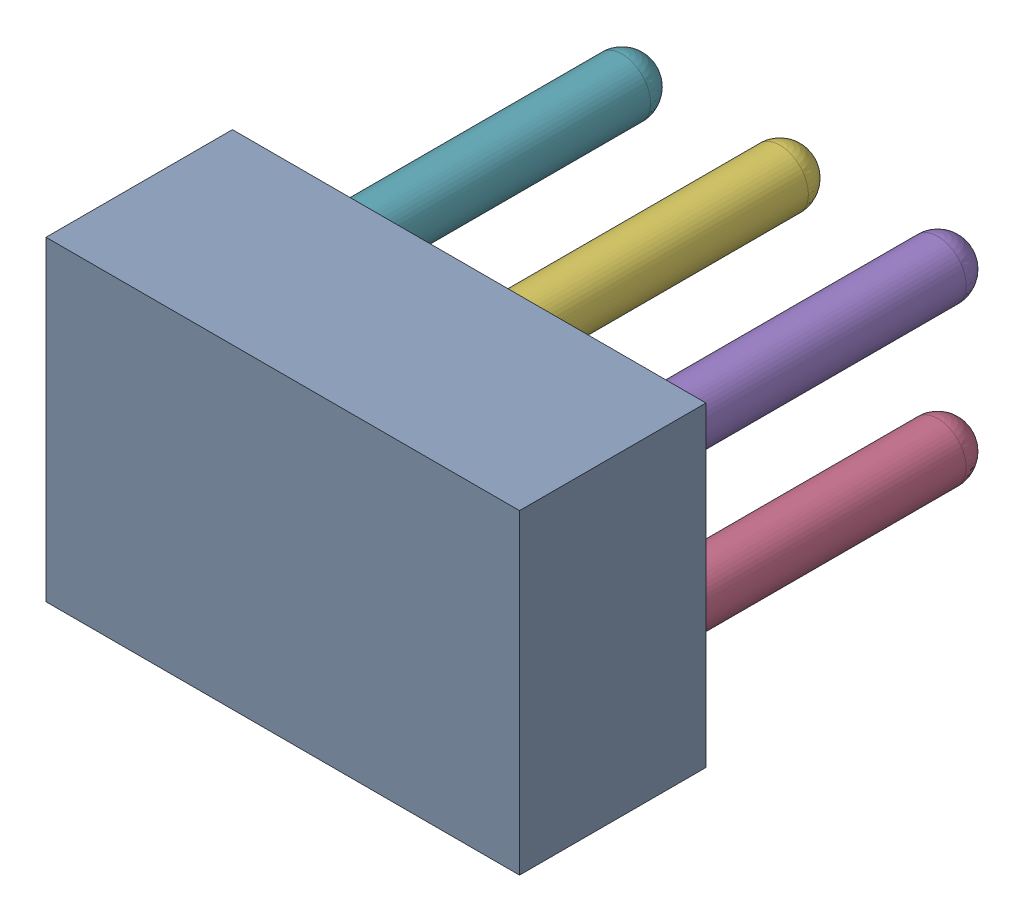
SolidWorks assembly Open CASCADE STEP translator 6.8 1.8.1, configuration Défaut. Lengths in mm.
Overall size (7.62 5.08 8.46).
7 component instances, 7 part files, 0 mates.
Components (placement in the parent):
- Body_1_5-1: Body_1_5 [Défaut] at origin size (7.62 5.08 3)
- Pin_1_2-1: Pin_1_2 [Défaut] x (0 -1 0) z (0 0 1) size (0.92 0.92 7.42)
- Pin_2_2-1: Pin_2_2 [Défaut] at (2.54 2.54 0) x (0 -1 0) z (0 0 1) size (0.92 0.92 7.42)
- Pin_3-1: Pin_3 [Défaut] at (5.08 5.08 0) x (0 -1 0) z (0 0 1) size (0.92 0.92 7.42)
- Pin_4-1: Pin_4 [Défaut] at (2.54 7.62 0) x (0 -1 0) z (0 0 1) size (0.92 0.92 7.42)
- Pin_5-1: Pin_5 [Défaut] at (0 5.08 0) x (0 -1 0) z (0 0 1) size (0.92 0.92 7.42)
- Pin_6-1: Pin_6 [Défaut] at (-2.54 2.54 0) x (0 -1 0) z (0 0 1) size (0.92 0.92 7.42)
